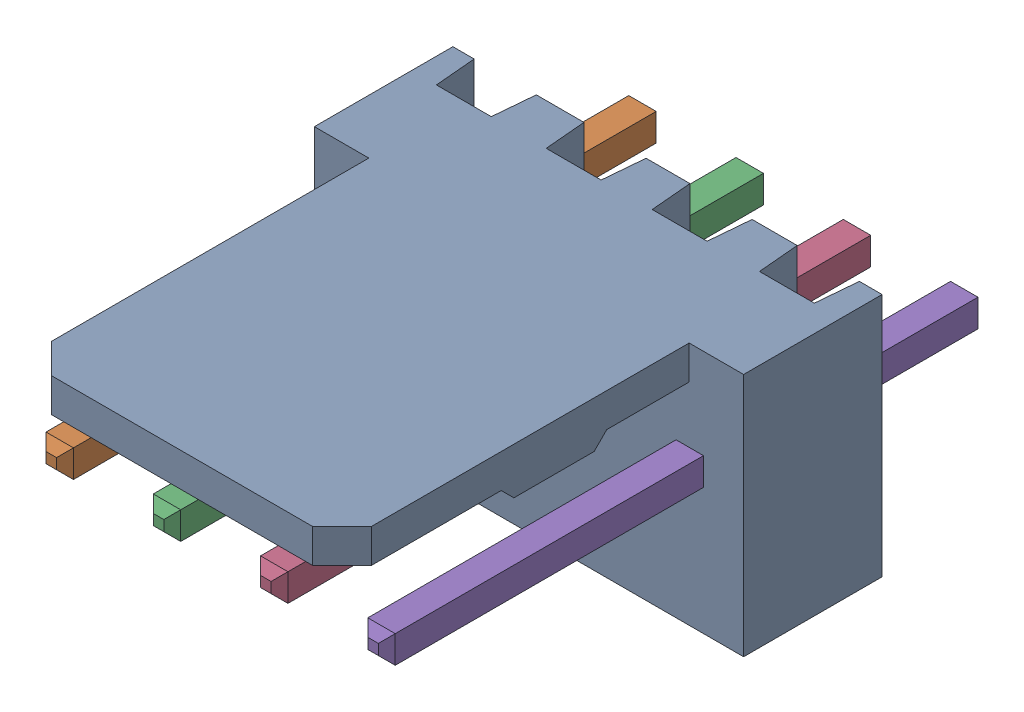
SolidWorks assembly Molex PCB 4 pin v3_1, configuration Default. Lengths in mm.
Overall size (10.16 5.79 14.92).
5 component instances, 2 part files, 0 mates.
Components (placement in the parent):
- BASE9710016 (2)-1: BASE9710016 (2) [Default] at (2.54 2.895 -8.22) size (10.16 5.79 11.5)
- PINO9710016 (2)-1: PINO9710016 (2) [Default] at (1.27 3.325 -0.72) size (0.65 0.65 14.2)
- PINO9710016 (2)-2: PINO9710016 (2) [Default] at (3.81 3.325 -0.72) size (0.65 0.65 14.2)
- PINO9710016 (2)-3: PINO9710016 (2) [Default] at (6.35 3.325 -0.72) size (0.65 0.65 14.2)
- PINO9710016 (2)-4: PINO9710016 (2) [Default] at (8.89 3.325 -0.72) size (0.65 0.65 14.2)
